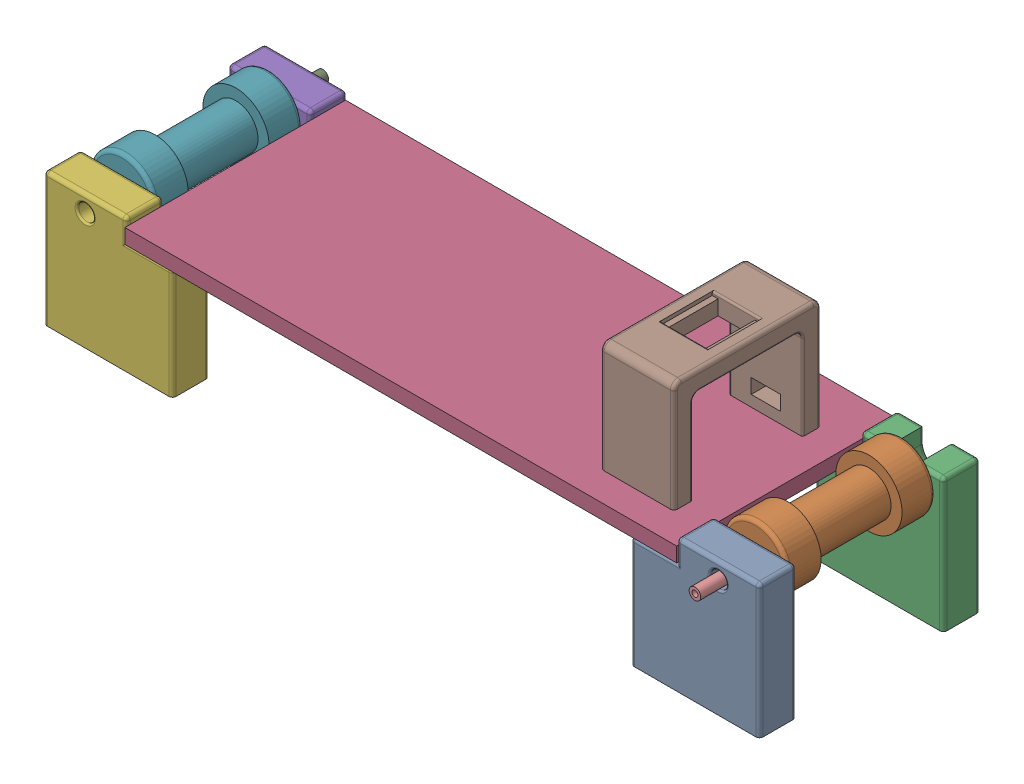
SolidWorks assembly AssemCC, configuration Default. Lengths in mm.
Overall size (495.3 163.19 181.15).
10 component instances, 6 part files, 17 mates.
Components (placement in the parent):
- Leg-6: Leg [Default] at (1149.2117 -249.103 315.7704) x (-1 0 0) z (0 0 -1) size (88.9 92.08 25.4)
- Conveyor roller DIY v3-4: Conveyor roller DIY v3 [Default] at (1120.6453 -168.458 188.7704) x (1 0 0) z (0 -1 0) size (45.72 101.6 45.72)
- DC Motor leg-5: DC Motor leg [Default] at (1149.2117 -249.103 188.7704) x (-1 0 0) z (0 0 -1) size (88.9 92.08 25.4)
- Surface-3: Surface [Default] at (711.0617 -172.268 315.9499) x (0 0 -1) z (0 -1 0) size (152.4 381 10.16)
- Leg-7: Leg [Default] at (653.9117 -249.103 162.4109) size (88.9 92.08 25.4)
- Leg-8: Leg [Default] at (653.9117 -249.103 289.4109) size (88.9 92.08 25.4)
- Conveyor roller DIY v3-5: Conveyor roller DIY v3 [Default] at (682.478 -168.458 289.4109) x (1 0 0) z (0 1 0) size (45.72 101.6 45.72)
- SensorBridge-1: SensorBridge [Default] at (1019.5692 -162.108 296.0267) x (0 0 -1) z (1 0 0) size (101.6 76.2 50.8)
- Hollow shaft-1: Hollow shaft [Default] at (682.478 -168.458 150.6598) x (1 0 0) z (0 -1 0) size (8 25.4 8)
- Hollow shaft-2: Hollow shaft [Default] at (1120.6453 -168.458 331.8059) x (1 0 0) z (0 1 0) size (8 25.4 8)
Mates (geometry in assembly coordinates):
- Coincident72: coincident anti-aligned: plane of Leg-6 through (1149.2117 -249.103 290.3704) normal (0 0 -1); plane of Conveyor roller DIY v3-4 through (1120.6453 -168.458 290.3704) normal (0 0 1)
- Coincident73: coincident anti-aligned: plane of Conveyor roller DIY v3-4 through (1120.6453 -168.458 188.7704) normal (0 0 -1); plane of DC Motor leg-5 through (1120.8867 -167.278 188.7704) normal (0 0 1)
- Concentric5: concentric anti-aligned: cylinder of Leg-6 through (1120.6453 -168.458 315.7704) axis (0 0 -1) radius 5.715; cylinder of Conveyor roller DIY v3-4 through (1120.6453 -168.458 282.7504) axis (0 0 1) radius 2.055
- Coincident86: coincident anti-aligned: plane of DC Motor leg-5 through (1092.0617 -172.268 163.3704) normal (0 1 0); plane of Surface-3 through (1092.0617 -172.268 163.5499) normal (0 -1 0)
- Coincident87: coincident anti-aligned: plane of DC Motor leg-5 through (1092.0617 -157.028 163.3704) normal (-1 0 0); plane of Surface-3 through (1092.0617 -172.268 315.9499) normal (1 0 0)
- Coincident88: coincident anti-aligned: plane of Surface-3 through (1092.0617 -172.268 163.5499) normal (0 -1 0); plane of Leg-7 through (711.0617 -172.268 187.8109) normal (0 1 0)
- Coincident89: coincident anti-aligned: plane of Surface-3 through (711.0617 -172.268 315.9499) normal (-1 0 0); plane of Leg-7 through (711.0617 -157.028 187.8109) normal (1 0 0)
- Coincident90: coincident anti-aligned: plane of Surface-3 through (1092.0617 -172.268 163.5499) normal (0 -1 0); plane of Leg-8 through (711.0617 -172.268 314.8109) normal (0 1 0)
- Coincident91: coincident anti-aligned: plane of Surface-3 through (711.0617 -172.268 315.9499) normal (-1 0 0); plane of Leg-8 through (711.0617 -157.028 314.8109) normal (1 0 0)
- Coincident92: coincident: line of Leg-6 through (1062.8517 -172.268 313.2304) axis (1 0 0); plane of Surface-3 through (1092.0617 -172.268 163.5499) normal (0 -1 0)
- Concentric6: concentric anti-aligned: circle of Leg-7; cylinder of Conveyor roller DIY v3-5 through (682.478 -168.458 195.4309) axis (0 0 -1) radius 2.055
- Coincident93: coincident anti-aligned: plane of Leg-8 through (653.9117 -249.103 289.4109) normal (0 0 -1); plane of Conveyor roller DIY v3-5 through (682.478 -168.458 289.4109) normal (0 0 1)
- Coincident94: coincident anti-aligned: plane of Leg-7 through (653.9117 -249.103 187.8109) normal (0 0 1); plane of Conveyor roller DIY v3-5 through (682.478 -168.458 187.8109) normal (0 0 -1)
- Coincident95: coincident anti-aligned: plane of Leg-6 through (1092.0617 -157.028 290.3704) normal (-1 0 0); plane of Surface-3 through (1092.0617 -172.268 315.9499) normal (1 0 0)
- Coincident96: coincident anti-aligned: plane of Surface-3 through (1092.0617 -162.108 315.9499) normal (0 1 0); plane of SensorBridge-1 through (1070.3692 -162.108 194.4267) normal (0 -1 0)
- Concentric9: concentric anti-aligned: cylinder of Conveyor roller DIY v3-5 through (682.478 -168.458 195.4309) axis (0 0 -1) radius 2.055; cylinder of Hollow shaft-1 through (682.478 -168.458 150.6598) axis (0 0 1) radius 2.05
- Concentric10: concentric anti-aligned: cylinder of Conveyor roller DIY v3-4 through (1120.6453 -168.458 282.7504) axis (0 0 1) radius 2.055; cylinder of Hollow shaft-2 through (1120.6453 -168.458 331.8059) axis (0 0 -1) radius 2.05
